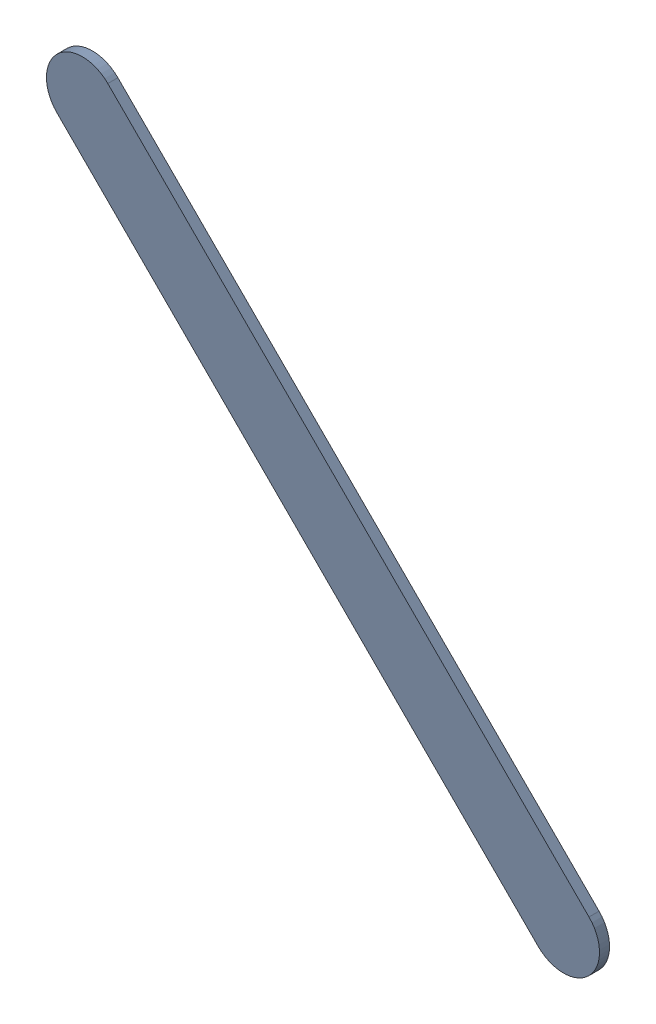
SolidWorks assembly Track (30.1mm,53.5mm)(31.8mm,51.8mm) on Top Layer, configuration Predeterminado. Lengths in mm.
Overall size (1.95 1.95 0.04).
2 component instances, 1 part files, 0 mates.
Components (placement in the parent):
- Track (30.1mm,53.5mm)(31.8mm,51.8mm) on Top Layer-1-1: Track (30.1mm,53.5mm)(31.8mm,51.8mm) on Top Layer-1 [Predeterminado] at (-68.317 -44.187 -0.0457) size (1.95 1.95 0.04)
  - Track (30.1mm,53.5mm)(31.8mm,51.8mm) on Top Layer-Part-1-1: Track (30.1mm,53.5mm)(31.8mm,51.8mm) on Top Layer-Part-1 [Predeterminado] at origin size (1.95 1.95 0.04)
